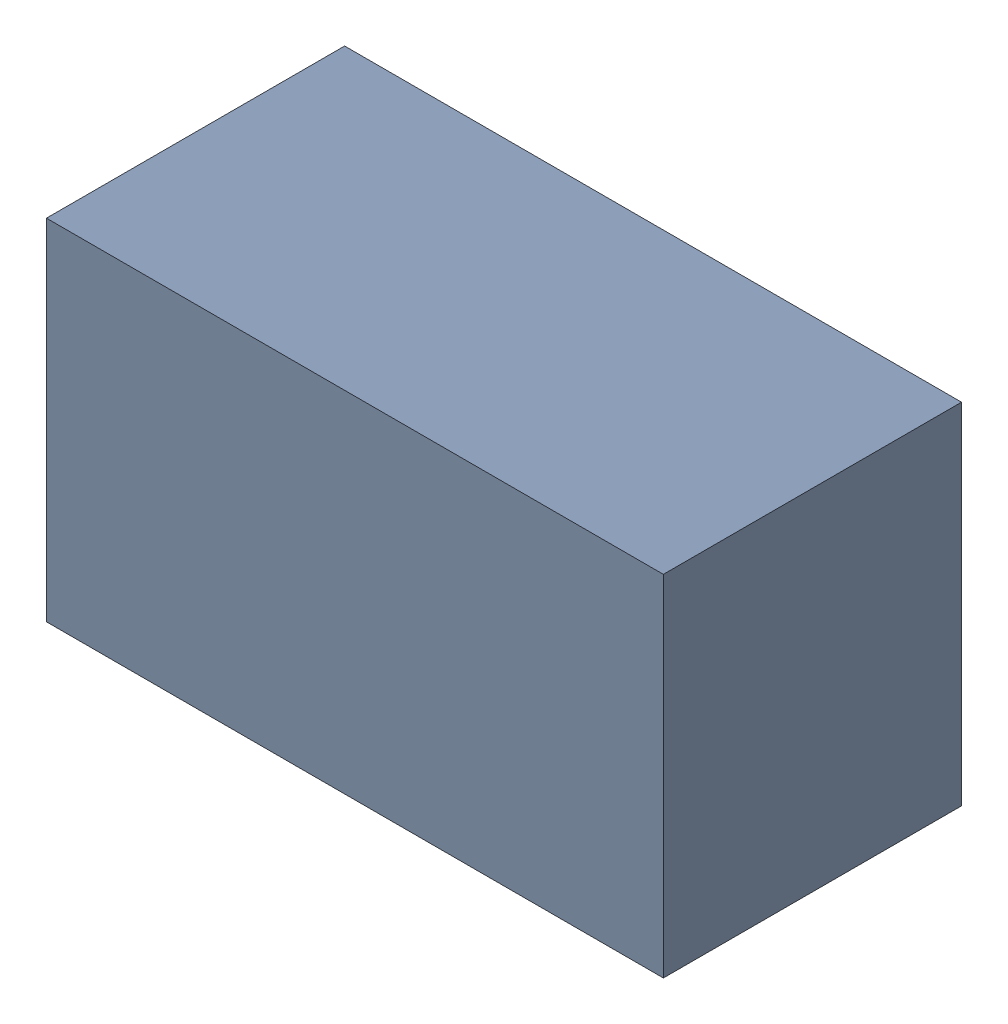
SolidWorks assembly U4, configuration Default. Lengths in mm.
Overall size (3 1.7 1.45).
2 component instances, 1 part files, 0 mates.
Components (placement in the parent):
- 870946240-1: 870946240 [Default] at (13.3342 34.2586 -3.0506) size (3 1.7 1.45)
  - Extruded_10-1: Extruded_10 [Default] at origin size (3 1.7 1.45)
